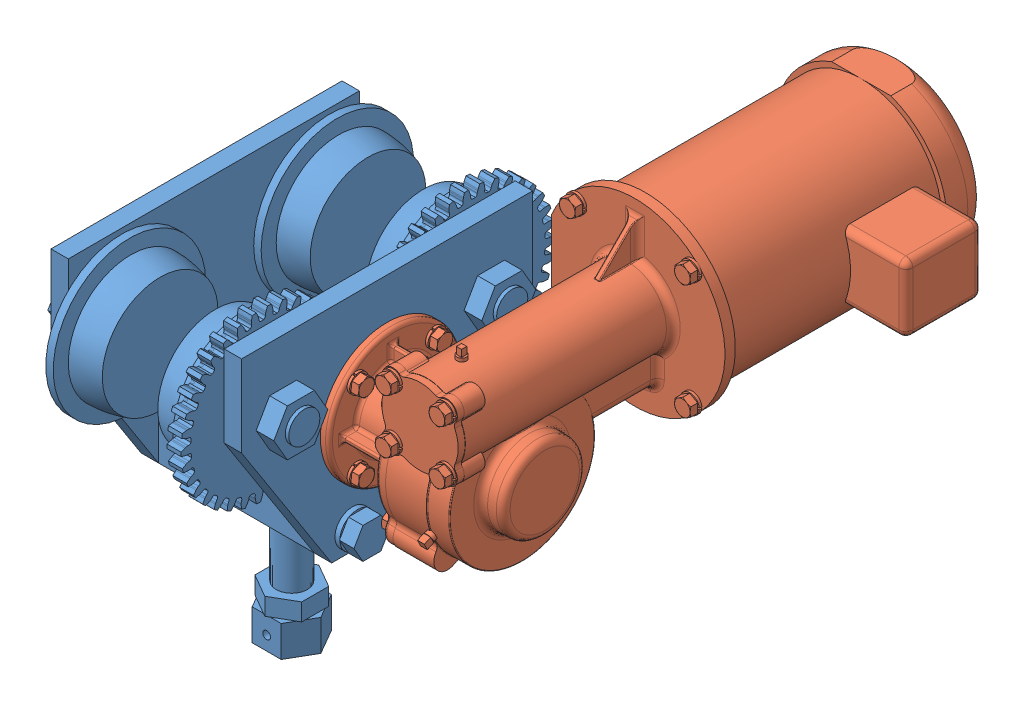
SolidWorks assembly M2632B-RH, configuration Default. Lengths in mm.
Overall size (421.68 387.47 540.72).
2 component instances, 2 part files, 3 mates.
Components (placement in the parent):
- Copy of M2632B-TROLLEY-SECTION^M2632B-RH-1: Copy of M2632B-TROLLEY-SECTION^M2632B-RH [S8x18.4#] at origin size (213.44 349.64 342.81) (virtual)
- Copy of SDT GEAR REDUCER TEMPLATE^M2632B-RH-1: Copy of SDT GEAR REDUCER TEMPLATE^M2632B-RH [Default] at (190.5 104.394 0) size (229.23 225.42 451.54) (virtual)
Mates (geometry in assembly coordinates):
- Coincident1: coincident aligned: plane of Copy of M2632B-TROLLEY-SECTION^M2632B-RH-1 through (0 0 0) normal (0 0 1); plane of Copy of SDT GEAR REDUCER TEMPLATE^M2632B-RH-1 through (190.5 104.394 0) normal (0 0 1)
- Coincident2: coincident aligned: plane of Copy of M2632B-TROLLEY-SECTION^M2632B-RH-1 through (0 104.394 0) normal (0 1 0); plane of Copy of SDT GEAR REDUCER TEMPLATE^M2632B-RH-1 through (190.5 104.394 0) normal (0 1 0)
- Distance1: distance = 14.2875 mm aligned: plane of Copy of SDT GEAR REDUCER TEMPLATE^M2632B-RH-1 through (85.725 104.394 0) normal (-1 0 0); plane of Copy of M2632B-TROLLEY-SECTION^M2632B-RH-1 through (71.4375 203.2 -133.35) normal (-1 0 0)
